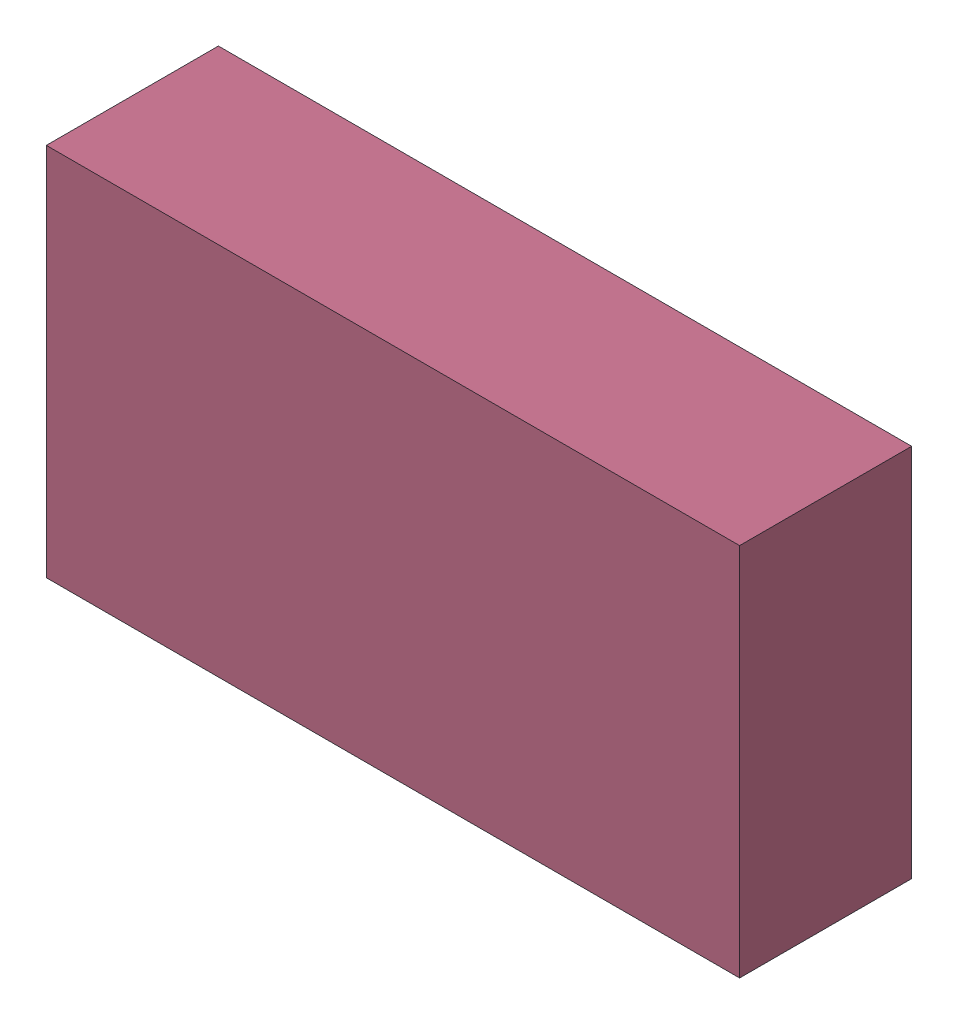
SolidWorks assembly Battery, configuration Défaut. Lengths in mm.
Overall size (139.63 67.7 31.63).
12 component instances, 3 part files, 8 mates.
Components (placement in the parent):
- Cell Holder-1: Cell Holder [Défaut] at (-49.8061 6.8542 0) size (135 10 30)
- Cell 26650-1: Cell 26650 [Défaut] at (-49.8061 7.8542 0) x (0.971207 0 -0.238239) z (0.238239 0 0.971207) size (26.15 65.7 26.15)
- Cell Holder-2: Cell Holder [Défaut] at (-49.8061 74.5542 0) x (1 0 0) z (0 0 -1) size (135 10 30)
- Cell Cover-2: Cell Cover [Défaut] at (17.6939 41.0542 0) x (0 0 -1) z (0 1 0) size (34 137 74) (hidden)
- Cell 26650-3: Cell 26650 [Défaut] at (-22.8061 7.8542 0) x (0.971207 0 -0.238239) z (0.238239 0 0.971207) size (26.15 65.7 26.15)
- Cell 26650-5: Cell 26650 [Défaut] at (4.1939 7.8542 0) x (0.971207 0 -0.238239) z (0.238239 0 0.971207) size (26.15 65.7 26.15)
- Cell 26650-13: Cell 26650 [Défaut] at (-76.8061 7.8542 0) x (0.971207 0 -0.238239) z (0.238239 0 0.971207) size (26.15 65.7 26.15)
- Cell 26650-14: Cell 26650 [Défaut] at (-103.8061 7.8542 0) x (0.971207 0 -0.238239) z (0.238239 0 0.971207) size (26.15 65.7 26.15)
- Cell 26650-15: Cell 26650 [Défaut] at (-49.8061 7.8542 0) x (0.971207 0 -0.238239) z (0.238239 0 0.971207) size (26.15 65.7 26.15)
- Cell 26650-16: Cell 26650 [Défaut] at (-76.8061 7.8542 0) x (0.971207 0 -0.238239) z (0.238239 0 0.971207) size (26.15 65.7 26.15)
- Cell 26650-17: Cell 26650 [Défaut] at (-22.8061 7.8542 0) x (0.971207 0 -0.238239) z (0.238239 0 0.971207) size (26.15 65.7 26.15)
- Cell 26650-18: Cell 26650 [Défaut] at (-49.8061 7.8542 0) x (0.971207 0 -0.238239) z (0.238239 0 0.971207) size (26.15 65.7 26.15)
Mates (geometry in assembly coordinates):
- Coaxiale1: concentric aligned: cylinder of Cell Holder-1 through (-49.8061 16.8542 0) axis (0 -1 0) radius 13.075; cylinder of Cell 26650-1 through (-49.8061 73.5542 0) axis (0 -1 0) radius 13.075
- Coïncidente4: coincident anti-aligned: plane of Cell Holder-1 through (4.1939 7.8542 0) normal (0 1 0); plane of Cell 26650-5 through (4.1939 7.8542 0) normal (0 -1 0)
- Coaxiale5: concentric anti-aligned: cylinder of Cell 26650-5 through (4.1939 73.5542 0) axis (0 -1 0) radius 13.075; cylinder of Cell Holder-2 through (4.1939 64.5542 0) axis (0 1 0) radius 13.075
- Coïncidente5: coincident anti-aligned: plane of Cell 26650-5 through (4.1939 73.5542 0) normal (0 1 0); plane of Cell Holder-2 through (4.1939 73.5542 0) normal (0 -1 0)
- Coaxiale6: concentric anti-aligned: cylinder of Cell Holder-2 through (-103.8061 64.5542 0) axis (0 1 0) radius 13.075; cylinder of Cell 26650-14 through (-103.8061 73.5542 0) axis (0 -1 0) radius 13.075
- Coïncidente7: coincident anti-aligned: plane of Cell Cover-2 through (17.6939 -4.5037 0) normal (0 0 -1)
- Coïncidente8: coincident anti-aligned: plane of Cell Holder-1 through (17.6939 16.8542 15) normal (1 0 0); plane of Cell Cover-2 through (17.6939 41.0542 0) normal (-1 0 0)
- Distance1: distance = 1.5 mm anti-aligned: plane of Cell Holder-2 through (-49.8061 74.5542 0) normal (0 1 0); plane of Cell Cover-2 through (-117.3061 76.0542 15) normal (0 -1 0)
